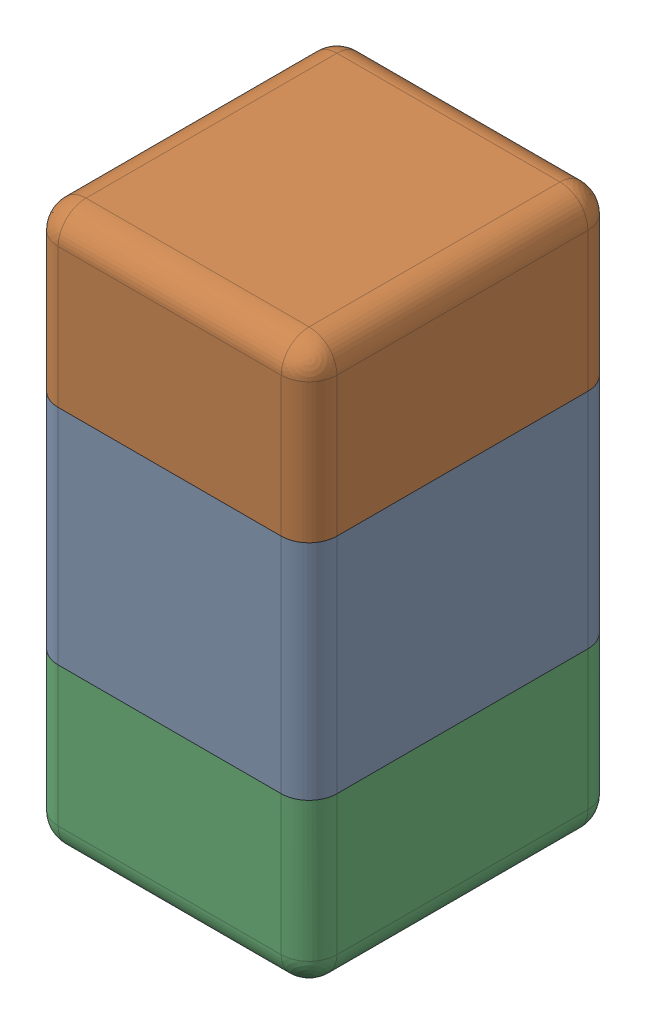
SolidWorks assembly C12, configuration Default. Lengths in mm.
Overall size (0.51 1.01 0.56).
5 component instances, 4 part files, 0 mates.
Components (placement in the parent):
- Cap_Kemet_C0402C562J5RACTU_eec-1: Cap_Kemet_C0402C562J5RACTU_eec [Default] at (150.75 90 -1.6914) x (0 -1 0) z (0 0 -1) size (1.01 0.51 0.56)
  - body_2-1: body_2 [Default] at origin size (0.4 0.5 0.55)
  - terminals-1: terminals [Default] at origin size (0.31 0.51 0.56)
  - terminals_2-1: terminals_2 [Default] at origin size (0.31 0.51 0.56)
  - value-1: value [Default] at (0 0 0.55) size (0.37 0.29 0.15)
